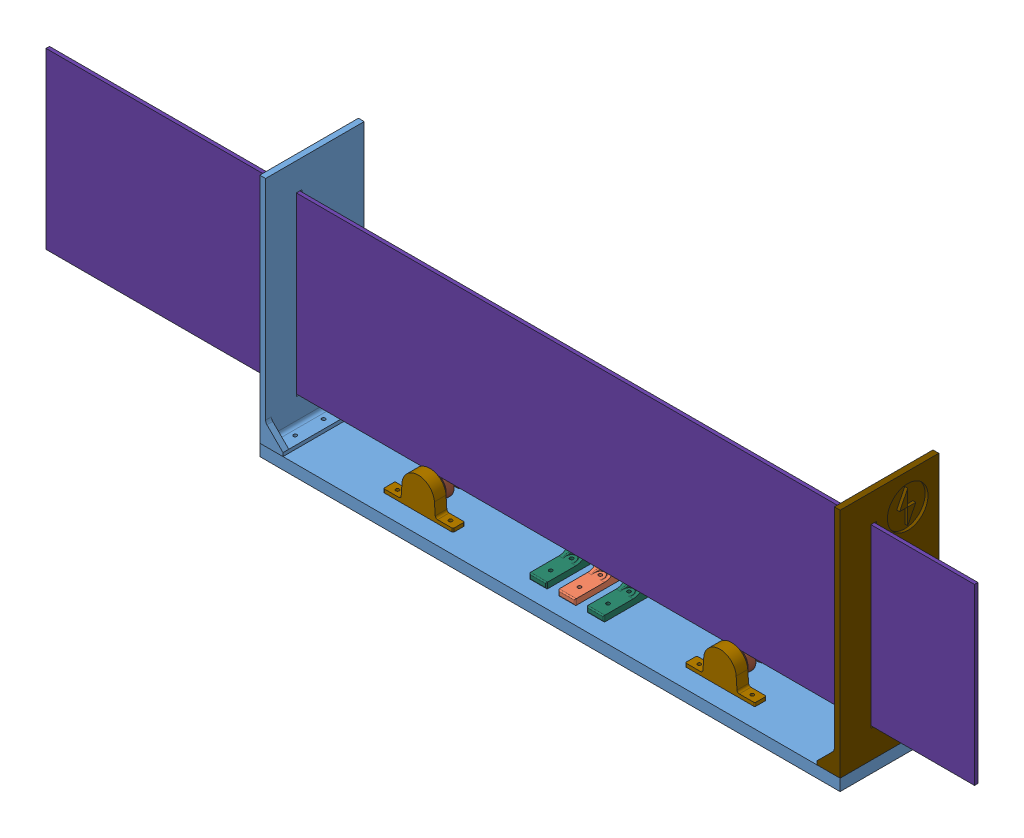
SolidWorks assembly Main, configuration Default. Lengths in mm.
Overall size (800 210 85).
38 component instances, 19 part files, 72 mates.
Components (placement in the parent):
- Ground__Plate-1: Ground__Plate [Default] at (340.4471 409.7021 600.6798) size (500 10 85)
- Motor__Mount-1: Motor__Mount [Default] at (391.2921 452.4908 552.5649) x (0 0 1) z (-1 0 0) size (60 86.5 26)
- Pinion-1: Pinion [Default] at (340.4471 470.7021 593.1798) x (-0.887245 0.461298 0) z (0 0 -1) size (53.93 53.92 10)
- Yellow__Gearbox__Motor-1: Yellow__Gearbox__Motor [Default] at (340.4471 459.7021 580.8048) x (0 0 1) z (-1 0 0) size (37.5 69 22) (flexible)
  - Gearbox__Base-1: Gearbox__Base [Default] at origin size (22 53 22)
  - Gearbox__Shaft-1: Gearbox__Shaft [Default] at (3.875 11 0) x (0 0.887245 -0.461298) z (-1 0 0) size (4.96 4.96 37.5)
  - CC__Motor__Base-1: CC__Motor__Base [Default] at (0 36.5 0) x (-1 0 0) z (0 0 -1) size (16 19 20)
  - CC__Motor__Cover-1: CC__Motor__Cover [Default] at (0 55.5 0) x (-1 0 0) z (0 0 -1) size (16.77 8.5 19.96)
  - CC__Motor__Attach-1: CC__Motor__Attach [Default] at (0 60.375 0) x (0 0 1) z (-1 0 0) size (15 17.75 18.25)
- Roller__Holder-1: Roller__Holder [Default] at (470.4471 409.7021 626.6798) x (0 0 -1) z (1 0 0) size (20 28 60)
- Roller__Holder-2: Roller__Holder [Default] at (470.4471 409.7021 574.6798) x (0 0 1) z (-1 0 0) size (20 28 60)
- Roller__Holder-3: Roller__Holder [Default] at (210.4471 409.7021 574.6798) x (0 0 1) z (-1 0 0) size (20 28 60)
- Roller__Holder-4: Roller__Holder [Default] at (210.4471 409.7021 626.6798) x (0 0 -1) z (1 0 0) size (20 28 60)
- Bearing__Type-1-1: Bearing__Type-1 [Default] at (204.4009 417.6392 601.6602) size (25.78 25.78 7) (flexible)
  - Bearing__Type-1__Inner-1: Bearing__Type-1__Inner [Default] at (6.0462 6.0629 8.5196) size (12 12 7)
  - Bearing__Type-1__Outer-1: Bearing__Type-1__Outer [Default] at (6.0462 6.0629 8.5196) x (0 0 1) z (0.190147 0.981756 0) size (7 22 22)
- Bearing__Type-1-2: Bearing__Type-1 [Default] at (203.7743 418.3365 582.6602) x (0.994006 -0.109329 0) z (0 0 1) size (25.78 25.78 7) (flexible)
  - Bearing__Type-1__Inner-1: Bearing__Type-1__Inner [Default] at (6.0462 6.0629 8.5196) size (12 12 7)
  - Bearing__Type-1__Outer-1: Bearing__Type-1__Outer [Default] at (6.0462 6.0629 8.5196) x (0 0 1) z (0.190147 0.981756 0) size (7 22 22)
- Bearing__Type-1-3: Bearing__Type-1 [Default] at (464.4009 417.6392 601.6602) size (25.78 25.78 7) (flexible)
  - Bearing__Type-1__Inner-1: Bearing__Type-1__Inner [Default] at (6.0462 6.0629 8.5196) size (12 12 7)
  - Bearing__Type-1__Outer-1: Bearing__Type-1__Outer [Default] at (6.0462 6.0629 8.5196) x (0 0 1) z (0.190147 0.981756 0) size (7 22 22)
- Bearing__Type-1-4: Bearing__Type-1 [Default] at (463.6433 418.5037 582.6602) x (0.990989 -0.133945 0) z (0 0 1) size (25.78 25.78 7) (flexible)
  - Bearing__Type-1__Inner-1: Bearing__Type-1__Inner [Default] at (6.0462 6.0629 8.5196) size (12 12 7)
  - Bearing__Type-1__Outer-1: Bearing__Type-1__Outer [Default] at (6.0462 6.0629 8.5196) x (0 0 1) z (0.190147 0.981756 0) size (7 22 22)
- Obstacle__Rack__Mount-1: Obstacle__Rack__Mount [Default] at (107.3536 351.3818 448.3023) size (201.06 23 27)
- Obstacle__Rack__Mount-2: Obstacle__Rack__Mount [Default] at (308.4136 351.3818 448.3023) size (201.06 23 27)
- Rack__20cm-1: Rack__20cm [Default] at (52.2712 388.1714 634.835) x (0 0 -1) z (1 0 0) size (10 10 201.06)
- Rack__20cm-2: Rack__20cm [Default] at (253.3331 388.1714 634.835) x (0 0 -1) z (1 0 0) size (10 10 201.06)
- End__Course__Trigger-1: End__Course__Trigger [Default] at (476.5722 437.7021 588.9298) size (6.5 13 6.5)
- End__Course__Trigger-2: End__Course__Trigger [Default] at (80.9522 437.7021 588.9298) size (6.5 13 6.5)
- End__Course__Mount-1: End__Course__Mount [Default] at (415.9891 452.4908 552.5649) x (0 0 1) z (-1 0 0) size (60 49.8 17.7)
- End__Course-1: End__Course [Default] at (367.4926 449.5021 585.5548) x (0 0 1) z (-1 0 0) size (6 20 19.6)
- End__Course__Mount-2: End__Course__Mount [Default] at (366.5952 452.4908 552.5649) x (0 0 1) z (-1 0 0) size (60 49.8 17.7)
- End__Course-2: End__Course [Default] at (313.4017 449.5021 591.5548) x (0 0 -1) z (1 0 0) size (6 20 19.6)
- Obstacle-1: Obstacle [Default] at (278.7622 509.7021 615.6798) x (0 0 -1) z (1 0 0) size (3 150 800)
- Obstacle__Support-1: Obstacle__Support [Default] at (585.4471 409.7021 600.6798) size (20 200 85)
- Obstacle__Support_2-1: Obstacle__Support_2 [Default] at (90.4471 409.7021 600.6798) size (20 200 85)
Mates (geometry in assembly coordinates):
- Width1: width anti-aligned: plane of Motor__Mount-1 through (333.0987 459.7021 579.3048) normal (-1 0 0); plane of Ground__Plate-1 through (347.7956 459.7021 579.3048) normal (1 0 0); plane of Motor__Mount-1 through (590.4471 399.7021 558.1798) normal (1 0 0); plane of Ground__Plate-1 through (90.4471 399.7021 558.1798) normal (-1 0 0)
- Coincident1: coincident anti-aligned: plane of Ground__Plate-1 through (340.4471 409.7021 600.6798) normal (0 1 0); plane of Motor__Mount-1 through (347.7956 409.7021 579.3048) normal (0 -1 0)
- Coincident2: coincident anti-aligned: plane of Motor__Mount-1 through (340.4471 457.2021 571.8048) normal (0 0 1); plane of Yellow__Gearbox__Motor-1/Gearbox__Base-1 through (351.4471 496.2021 571.8048) normal (0 0 -1)
- Concentric1: concentric anti-aligned: cylinder of Motor__Mount-1 through (349.4471 491.2021 568.8048) axis (0 0 1) radius 1.5; cylinder of Yellow__Gearbox__Motor-1/Gearbox__Base-1 through (349.4471 491.2021 591.8048) axis (0 0 -1) radius 1.5
- Concentric2: concentric anti-aligned: cylinder of Motor__Mount-1 through (331.4471 491.2021 568.8048) axis (0 0 1) radius 1.5; cylinder of Yellow__Gearbox__Motor-1/Gearbox__Base-1 through (331.4471 491.2021 591.8048) axis (0 0 -1) radius 1.5
- Concentric3: concentric aligned: cylinder of Pinion-1 through (340.4471 470.7021 601.1798) axis (0 0 -1) radius 2.75; cylinder of Yellow__Gearbox__Motor-1/Gearbox__Shaft-1 through (340.4471 470.7021 589.6798) axis (0 0 -1) radius 2.48
- Parallel1: parallel aligned: plane of Pinion-1 through (339.5476 468.972 601.1798) normal (0.461298 0.887245 0); plane of Yellow__Gearbox__Motor-1/Gearbox__Shaft-1 through (341.3697 472.4766 600.1798) normal (0.461298 0.887245 0)
- Coincident4: coincident anti-aligned: plane of Pinion-1 through (340.4471 470.7021 591.1798) normal (0 0 -1); plane of Yellow__Gearbox__Motor-1/Gearbox__Shaft-1 through (340.4471 470.7021 591.1798) normal (0 0 1)
- Parallel2: parallel anti-aligned: plane of Ground__Plate-1 through (90.4471 399.7021 643.1798) normal (0 0 1); plane of Roller__Holder-4 through (210.4471 423.7021 616.6798) normal (0 0 -1)
- Parallel3: parallel anti-aligned: plane of Ground__Plate-1 through (90.4471 399.7021 643.1798) normal (0 0 1); plane of Roller__Holder-1 through (470.4471 423.7021 616.6798) normal (0 0 -1)
- Parallel4: parallel aligned: plane of Ground__Plate-1 through (90.4471 399.7021 643.1798) normal (0 0 1); plane of Roller__Holder-3 through (210.4471 423.7021 584.6798) normal (0 0 1)
- Parallel6: parallel anti-aligned: plane of Ground__Plate-1 through (90.4471 399.7021 643.1798) normal (0 0 1); plane of Roller__Holder-2 through (470.4471 423.7021 574.6798) normal (0 0 -1)
- Coincident10: coincident anti-aligned: plane of Ground__Plate-1 through (340.4471 409.7021 600.6798) normal (0 1 0); plane of Roller__Holder-4 through (225.4471 409.7021 616.6798) normal (0 -1 0)
- Coincident11: coincident anti-aligned: plane of Ground__Plate-1 through (340.4471 409.7021 600.6798) normal (0 1 0); plane of Roller__Holder-3 through (195.4471 409.7021 584.6798) normal (0 -1 0)
- Concentric4: concentric anti-aligned: cylinder of Roller__Holder-3 through (210.4471 423.7021 594.6798) axis (0 0 -1) radius 3.95; cylinder of Roller__Holder-4 through (210.4471 423.7021 606.6798) axis (0 0 1) radius 3.95
- HERE1: distance = 32 mm anti-aligned: plane of Roller__Holder-3 through (210.4471 423.7021 584.6798) normal (0 0 1); plane of Roller__Holder-4 through (210.4471 423.7021 616.6798) normal (0 0 -1)
- Coincident13: coincident anti-aligned: plane of Ground__Plate-1 through (340.4471 409.7021 600.6798) normal (0 1 0); plane of Roller__Holder-2 through (455.4471 409.7021 584.6798) normal (0 -1 0)
- Coincident14: coincident anti-aligned: plane of Ground__Plate-1 through (340.4471 409.7021 600.6798) normal (0 1 0); plane of Roller__Holder-1 through (485.4471 409.7021 616.6798) normal (0 -1 0)
- Concentric5: concentric anti-aligned: cylinder of Roller__Holder-1 through (470.4471 423.7021 606.6798) axis (0 0 1) radius 3.95; cylinder of Roller__Holder-2 through (470.4471 423.7021 594.6798) axis (0 0 -1) radius 3.95
- HERE2: distance = 32 mm anti-aligned: plane of Roller__Holder-2 through (470.4471 423.7021 584.6798) normal (0 0 1); plane of Roller__Holder-1 through (470.4471 423.7021 616.6798) normal (0 0 -1)
- HERE3: width aligned: plane of Roller__Holder-4 through (210.4471 423.7021 626.6798) normal (0 0 1); plane of Ground__Plate-1 through (210.4471 423.7021 574.6798) normal (0 0 -1); plane of Roller__Holder-3 through (90.4471 399.7021 643.1798) normal (0 0 1); plane of Ground__Plate-1 through (90.4471 399.7021 558.1798) normal (0 0 -1)
- Coincident17: coincident aligned: plane of Roller__Holder-1 through (470.4471 423.7021 626.6798) normal (0 0 1); plane of Roller__Holder-4 through (210.4471 423.7021 626.6798) normal (0 0 1)
- Distance4: distance = 200 mm anti-aligned: plane of Roller__Holder-1 through (440.4471 412.7021 626.6798) normal (-1 0 0); plane of Roller__Holder-4 through (240.4471 412.7021 626.6798) normal (1 0 0)
- Width3: width aligned: plane of Roller__Holder-1 through (500.4471 412.7021 626.6798) normal (1 0 0); plane of Ground__Plate-1 through (180.4471 412.7021 626.6798) normal (-1 0 0); plane of Roller__Holder-4 through (590.4471 399.7021 558.1798) normal (1 0 0); plane of Ground__Plate-1 through (90.4471 399.7021 558.1798) normal (-1 0 0)
- Concentric6: concentric aligned: cylinder of Roller__Holder-3 through (210.4471 423.7021 594.6798) axis (0 0 -1) radius 3.95; cylinder of Bearing__Type-1-2/Bearing__Type-1__Inner-1 through (210.4471 423.7021 594.6798) axis (0 0 -1) radius 4
- Concentric7: concentric anti-aligned: cylinder of Roller__Holder-4 through (210.4471 423.7021 606.6798) axis (0 0 1) radius 3.95; cylinder of Bearing__Type-1-1/Bearing__Type-1__Inner-1 through (210.4471 423.7021 613.6798) axis (0 0 -1) radius 4
- Concentric8: concentric aligned: cylinder of Roller__Holder-2 through (470.4471 423.7021 594.6798) axis (0 0 -1) radius 3.95; cylinder of Bearing__Type-1-4/Bearing__Type-1__Inner-1 through (470.4471 423.7021 594.6798) axis (0 0 -1) radius 4
- Concentric9: concentric anti-aligned: cylinder of Roller__Holder-1 through (470.4471 423.7021 606.6798) axis (0 0 1) radius 3.95; cylinder of Bearing__Type-1-3/Bearing__Type-1__Inner-1 through (470.4471 423.7021 613.6798) axis (0 0 -1) radius 4
- Coincident20: coincident aligned: plane of Roller__Holder-1 through (470.4471 423.7021 606.6798) normal (0 0 -1); plane of Bearing__Type-1-3/Bearing__Type-1__Inner-1 through (470.4471 423.7021 606.6798) normal (0 0 -1)
- Coincident21: coincident aligned: plane of Roller__Holder-2 through (470.4471 423.7021 594.6798) normal (0 0 1); plane of Bearing__Type-1-4/Bearing__Type-1__Inner-1 through (470.4471 423.7021 594.6798) normal (0 0 1)
- Coincident22: coincident aligned: plane of Roller__Holder-4 through (210.4471 423.7021 606.6798) normal (0 0 -1); plane of Bearing__Type-1-1/Bearing__Type-1__Inner-1 through (210.4471 423.7021 606.6798) normal (0 0 -1)
- Coincident23: coincident aligned: plane of Roller__Holder-3 through (210.4471 423.7021 594.6798) normal (0 0 1); plane of Bearing__Type-1-2/Bearing__Type-1__Inner-1 through (210.4471 423.7021 594.6798) normal (0 0 1)
- Coincident24: coincident anti-aligned: plane of Obstacle__Rack__Mount-1 through (278.7622 457.7021 608.6798) normal (1 0 0); plane of Obstacle__Rack__Mount-2 through (278.7622 457.7021 608.6798) normal (-1 0 0)
- Coincident25: coincident aligned: plane of Obstacle__Rack__Mount-1 through (77.7022 434.7021 585.6798) normal (0 0 -1); plane of Obstacle__Rack__Mount-2 through (278.7622 434.7021 585.6798) normal (0 0 -1)
- Coincident26: coincident aligned: plane of Obstacle__Rack__Mount-1 through (178.2322 434.7021 599.1798) normal (0 -1 0); plane of Obstacle__Rack__Mount-2 through (379.2922 434.7021 599.1798) normal (0 -1 0)
- Tangent1: tangent anti-aligned: cylinder of Bearing__Type-1-3/Bearing__Type-1__Outer-1 through (470.4471 423.7021 613.6798) axis (0 0 -1) radius 11; plane of Obstacle__Rack__Mount-2 through (379.2922 434.7021 599.1798) normal (0 -1 0)
- Coincident27: coincident aligned: plane of Rack__20cm-1 through (197.0789 447.7021 592.1798) normal (0 0 -1); plane of Rack__20cm-2 through (398.1408 447.7021 592.1798) normal (0 0 -1)
- Coincident28: coincident aligned: plane of Rack__20cm-1 through (39.5071 437.7021 602.0802) normal (0 -1 0); plane of Rack__20cm-2 through (240.569 437.7021 602.0802) normal (0 -1 0)
- Coincident29: coincident anti-aligned: plane of Rack__20cm-1 through (278.7603 443.2021 602.1798) normal (1 0 0); plane of Rack__20cm-2 through (278.7603 435.2021 602.1798) normal (-1 0 0)
- Coincident30: coincident anti-aligned: plane of Obstacle__Rack__Mount-2 through (379.2922 437.7021 599.1798) normal (0 1 0); plane of Rack__20cm-1 through (39.5071 437.7021 602.0802) normal (0 -1 0)
- Tangent2: tangent anti-aligned: cylinder of Bearing__Type-1-2/Bearing__Type-1__Outer-1 through (210.4471 423.7021 594.6798) axis (0 0 -1) radius 11; plane of Obstacle__Rack__Mount-1 through (178.2322 434.7021 599.1798) normal (0 -1 0)
- Width5: width aligned: plane of Rack__20cm-1 through (197.0789 447.7021 592.1798) normal (0 0 -1); plane of Obstacle__Rack__Mount-2 through (197.0789 447.7021 602.1798) normal (0 0 1); plane of Rack__20cm-1 through (278.7622 457.7021 608.6798) normal (0 0 -1); plane of Obstacle__Rack__Mount-2 through (278.7622 434.7021 585.6798) normal (0 0 -1)
- Coincident31: coincident aligned: plane of Obstacle__Rack__Mount-2 through (479.8222 457.7021 608.6798) normal (1 0 0); plane of Rack__20cm-2 through (479.8222 443.2021 602.1798) normal (1 0 0)
- Width6: width anti-aligned: plane of Rack__20cm-1 through (197.0789 447.7021 592.1798) normal (0 0 -1); plane of Pinion-1 through (197.0789 447.7021 602.1798) normal (0 0 1); plane of Rack__20cm-1 through (340.4471 470.7021 601.1798) normal (0 0 1); plane of Pinion-1 through (340.4471 470.7021 593.1798) normal (0 0 -1)
- Coincident32: coincident aligned: plane of Obstacle__Rack__Mount-2 through (278.7622 434.7021 585.6798) normal (0 0 -1); plane of End__Course__Trigger-1 through (473.3222 450.7021 585.6798) normal (0 0 -1)
- Coincident33: coincident anti-aligned: plane of Obstacle__Rack__Mount-2 through (379.2922 437.7021 599.1798) normal (0 1 0); plane of End__Course__Trigger-1 through (476.5722 437.7021 588.9298) normal (0 -1 0)
- Coincident34: coincident aligned: plane of Obstacle__Rack__Mount-2 through (479.8222 457.7021 608.6798) normal (1 0 0); plane of End__Course__Trigger-1 through (479.8222 450.7021 585.6798) normal (1 0 0)
- Coincident36: coincident aligned: plane of Obstacle__Rack__Mount-1 through (77.7022 434.7021 585.6798) normal (0 0 -1); plane of End__Course__Trigger-2 through (77.7022 450.7021 585.6798) normal (0 0 -1)
- Coincident37: coincident anti-aligned: plane of Obstacle__Rack__Mount-1 through (178.2322 437.7021 599.1798) normal (0 1 0); plane of End__Course__Trigger-2 through (80.9522 437.7021 588.9298) normal (0 -1 0)
- Coincident38: coincident aligned: plane of Obstacle__Rack__Mount-1 through (77.7022 457.7021 608.6798) normal (-1 0 0); plane of End__Course__Trigger-2 through (77.7022 450.7021 585.6798) normal (-1 0 0)
- Coincident39: coincident anti-aligned: plane of Ground__Plate-1 through (340.4471 409.7021 600.6798) normal (0 1 0); plane of End__Course__Mount-1 through (372.4926 409.7021 579.3048) normal (0 -1 0)
- HERE4: distance = 10 mm anti-aligned: plane of End__Course__Mount-1 through (357.7956 459.7021 579.3048) normal (-1 0 0); plane of Motor__Mount-1 through (347.7956 459.7021 579.3048) normal (1 0 0)
- Coincident42: coincident aligned: plane of End__Course__Mount-1 through (372.4926 459.7021 579.3048) normal (1 0 0); plane of End__Course-1 through (372.4926 459.5021 591.5548) normal (1 0 0)
- Coincident43: coincident aligned: plane of Motor__Mount-1 through (340.4471 457.2021 568.8048) normal (0 0 -1); plane of End__Course__Mount-1 through (365.1441 457.2021 568.8048) normal (0 0 -1)
- Coincident44: coincident aligned: plane of End__Course__Mount-1 through (415.9891 459.5021 552.5649) normal (0 1 0); plane of End__Course-1 through (362.4926 459.5021 591.5548) normal (0 1 0)
- Coincident45: coincident anti-aligned: plane of End__Course__Mount-1 through (393.7661 459.5021 585.5548) normal (0 0 1); plane of End__Course-1 through (367.4926 449.5021 585.5548) normal (0 0 -1)
- Coincident46: coincident aligned: plane of Motor__Mount-1 through (340.4471 457.2021 568.8048) normal (0 0 -1); plane of End__Course__Mount-2 through (315.7502 457.2021 568.8048) normal (0 0 -1)
- Coincident47: coincident anti-aligned: plane of Ground__Plate-1 through (340.4471 409.7021 600.6798) normal (0 1 0); plane of End__Course__Mount-2 through (323.0987 409.7021 579.3048) normal (0 -1 0)
- HERE5: distance = 10 mm anti-aligned: plane of End__Course__Mount-2 through (323.0987 459.7021 579.3048) normal (1 0 0); plane of Motor__Mount-1 through (333.0987 459.7021 579.3048) normal (-1 0 0)
- Coincident49: coincident aligned: plane of End__Course__Mount-2 through (366.5952 459.5021 552.5649) normal (0 1 0); plane of End__Course-2 through (318.4017 459.5021 585.5548) normal (0 1 0)
- Coincident50: coincident anti-aligned: plane of End__Course__Mount-2 through (344.3722 459.5021 585.5548) normal (0 0 1); plane of End__Course-2 through (313.4017 449.5021 585.5548) normal (0 0 -1)
- Coincident51: coincident aligned: plane of End__Course__Mount-2 through (308.4017 459.7021 579.3048) normal (-1 0 0); plane of End__Course-2 through (308.4017 459.5021 585.5548) normal (-1 0 0)
- Coincident52: coincident anti-aligned: plane of Obstacle__Rack__Mount-2 through (278.7622 457.7021 612.6798) normal (0 0 1); plane of Obstacle-1 through (278.7622 509.7021 612.6798) normal (0 0 -1)
- Coincident54: coincident aligned: plane of Obstacle__Rack__Mount-2 through (379.2922 434.7021 599.1798) normal (0 -1 0); plane of Obstacle-1 through (678.7622 434.7021 612.6798) normal (0 -1 0)
- Width7: width anti-aligned: plane of Obstacle-1 through (278.7622 509.7021 615.6798) normal (0 0 1); plane of Roller__Holder-1 through (278.7622 434.7021 585.6798) normal (0 0 -1); plane of Obstacle__Rack__Mount-2 through (470.4471 423.7021 616.6798) normal (0 0 -1); plane of Roller__Holder-2 through (470.4471 423.7021 584.6798) normal (0 0 1)
- Width8: width aligned: plane of Obstacle-1 through (678.7622 584.7021 612.6798) normal (1 0 0); plane of Obstacle__Rack__Mount-2 through (-121.2378 584.7021 612.6798) normal (-1 0 0); plane of Obstacle-1 through (479.8222 457.7021 608.6798) normal (1 0 0); plane of Obstacle__Rack__Mount-1 through (77.7022 457.7021 608.6798) normal (-1 0 0)
- Coincident55: coincident anti-aligned: plane of Ground__Plate-1 through (340.4471 409.7021 600.6798) normal (0 1 0); plane of Obstacle__Support-1 through (590.4471 409.7021 643.1798) normal (0 -1 0)
- Coincident56: coincident aligned: plane of Ground__Plate-1 through (90.4471 399.7021 643.1798) normal (0 0 1); plane of Obstacle__Support-1 through (590.4471 409.7021 643.1798) normal (0 0 1)
- Coincident57: coincident aligned: plane of Ground__Plate-1 through (590.4471 399.7021 558.1798) normal (1 0 0); plane of Obstacle__Support-1 through (590.4471 409.7021 600.6798) normal (1 0 0)
- Coincident58: coincident aligned: plane of Ground__Plate-1 through (90.4471 399.7021 643.1798) normal (0 0 1); plane of Obstacle__Support_2-1 through (95.4471 409.7021 643.1798) normal (0 0 1)
- Coincident59: coincident aligned: plane of Ground__Plate-1 through (90.4471 399.7021 558.1798) normal (-1 0 0); plane of Obstacle__Support_2-1 through (90.4471 409.7021 600.6798) normal (-1 0 0)
- Coincident60: coincident anti-aligned: plane of Ground__Plate-1 through (340.4471 409.7021 600.6798) normal (0 1 0); plane of Obstacle__Support_2-1 through (95.4471 409.7021 643.1798) normal (0 -1 0)
